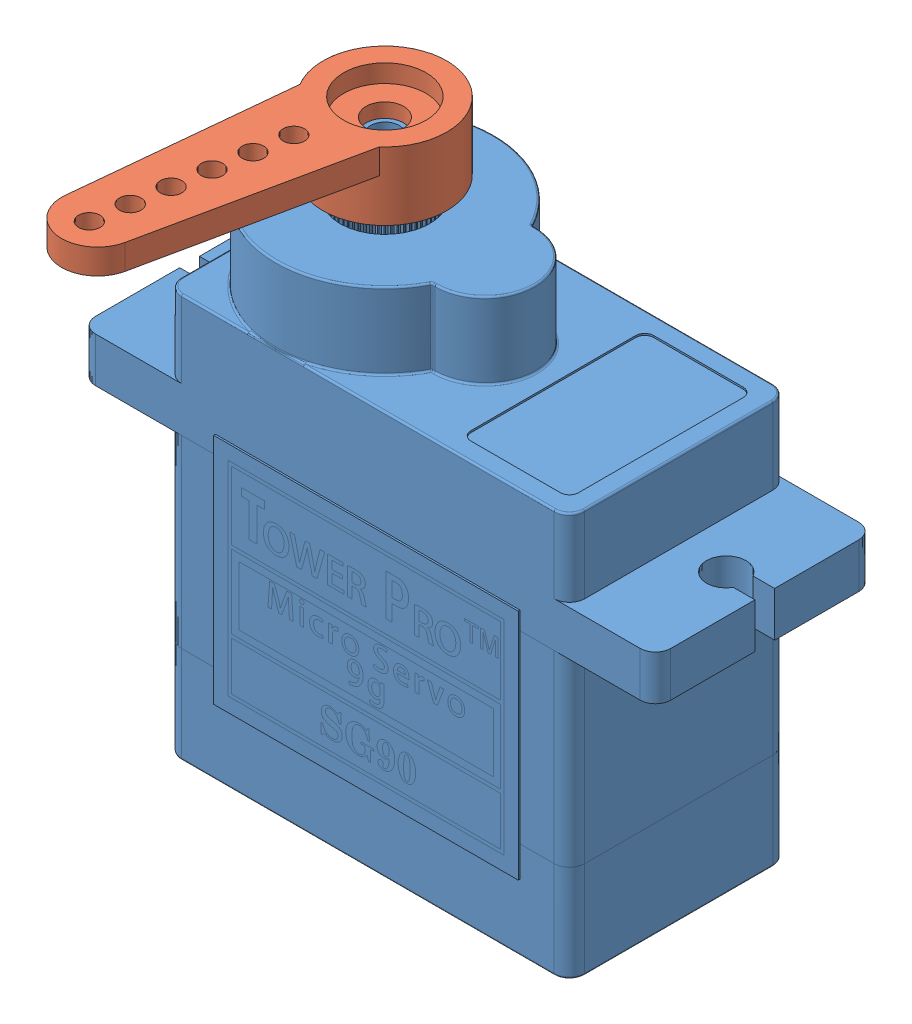
SolidWorks assembly SG90 - Micro Servo Assembly, configuration Default. Lengths in mm.
Overall size (32.1 31.75 22.59).
2 component instances, 2 part files, 2 mates.
Components (placement in the parent):
- SG90 - Micro Servo 9g - Tower Pro.1-2: SG90 - Micro Servo 9g - Tower Pro.1 [Peça] at origin size (32.1 29.95 12.4)
- SG90 - Micro Servo 9g - Tower Pro.2-2: SG90 - Micro Servo 9g - Tower Pro.2 [Peça] at (-5.15 21.1 0) x (0.153134 0 -0.988205) z (0.988205 0 0.153134) size (19.5 3.8 6.9)
Mates (geometry in assembly coordinates):
- Coincident2: coincident anti-aligned: plane of SG90 - Micro Servo 9g - Tower Pro.1-2 through (-5.15 19.3 0) normal (0 1 0); plane of SG90 - Micro Servo 9g - Tower Pro.2-2 through (-5.15 19.3 0) normal (0 -1 0)
- Concentric1: concentric anti-aligned: circle of SG90 - Micro Servo 9g - Tower Pro.1-2; circle of SG90 - Micro Servo 9g - Tower Pro.2-2
